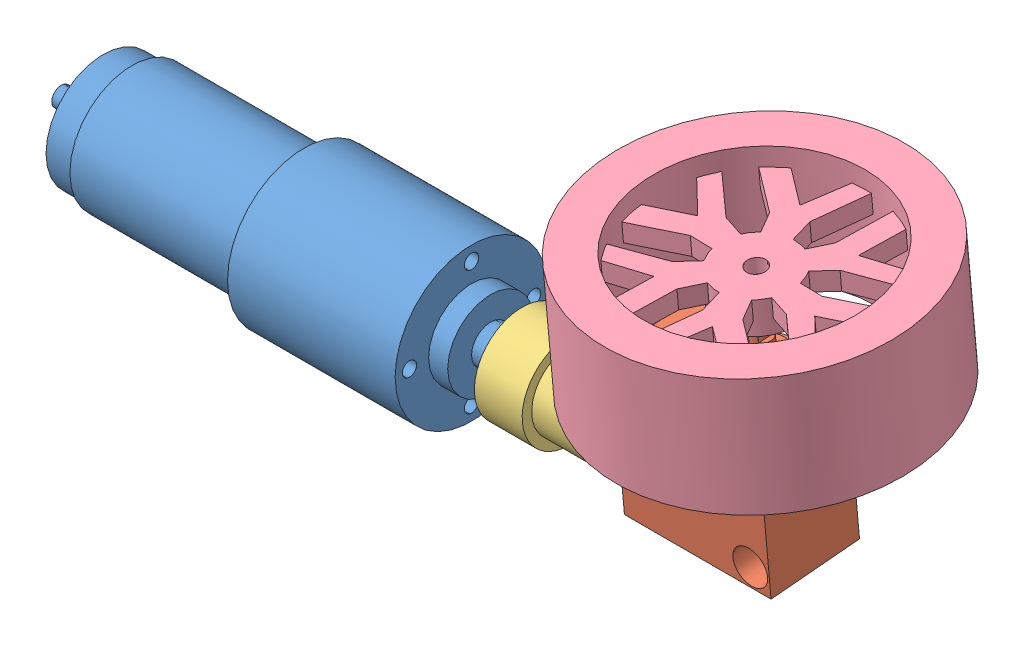
SolidWorks assembly GearHpcWithFixAndMotor, configuration Défaut. Lengths in mm.
Overall size (194.02 70.17 90.63).
4 component instances, 4 part files, 5 mates.
Components (placement in the parent):
- 2642W_CR_with_30-1S-1: 2642W_CR_with_30-1S [Défaut] at (-49.0991 3.5572 -5.6024) size (106.5 32 32)
- GearHpc90Degree-1: GearHpc90Degree [Défaut] at (108.1009 -3.9121 -6.2802) x (-1 0 0) z (0 0.090384 -0.995907) size (50.7 50.7 18.6)
- GearHpc90DegreeLinkWithMotor-1: GearHpc90DegreeLinkWithMotor [Défaut] at (57.4009 3.5572 -5.6024) x (0 0.216391 -0.976307) z (-1 0 0) size (20 20 22)
- Wheel-Traction-63x26mm-1: Wheel-Traction-63x26mm [Défaut] at (100.6009 27.8272 -3.3997) x (0.632468 0.07001 -0.771416) z (0 0.995907 0.090384) size (63 63 26)
Mates (geometry in assembly coordinates):
- Coaxiale1: concentric aligned: cylinder of GearHpc90Degree-1 through (57.4009 3.5572 -5.6024) axis (-1 0 0) radius 2; cylinder of GearHpc90DegreeLinkWithMotor-1 through (69.4009 3.5572 -5.6024) axis (-1 0 0) radius 8
- Coïncidente2: coincident anti-aligned: plane of GearHpc90Degree-1 through (69.4009 -3.9121 -6.2802) normal (-1 0 0); plane of GearHpc90DegreeLinkWithMotor-1 through (69.4009 3.5572 -5.6024) normal (1 0 0)
- Coaxiale2: concentric anti-aligned: cylinder of 2642W_CR_with_30-1S-1 through (-49.0991 3.5572 -5.6024) axis (-1 0 0) radius 4; cylinder of GearHpc90DegreeLinkWithMotor-1 through (47.4009 3.5572 -5.6024) axis (1 0 0) radius 10
- Coïncidente4: coincident anti-aligned: plane of 2642W_CR_with_30-1S-1 through (47.4009 3.5572 -5.6024) normal (1 0 0); plane of GearHpc90DegreeLinkWithMotor-1 through (47.4009 3.5572 -5.6024) normal (-1 0 0)
- Coaxiale3: concentric aligned: cylinder of GearHpc90Degree-1 through (100.6009 46.5804 -1.6978) axis (0 0.995907 0.090384) radius 2; cylinder of Wheel-Traction-63x26mm-1 through (100.6009 27.8272 -3.3997) axis (0 0.995907 0.090384) radius 2
